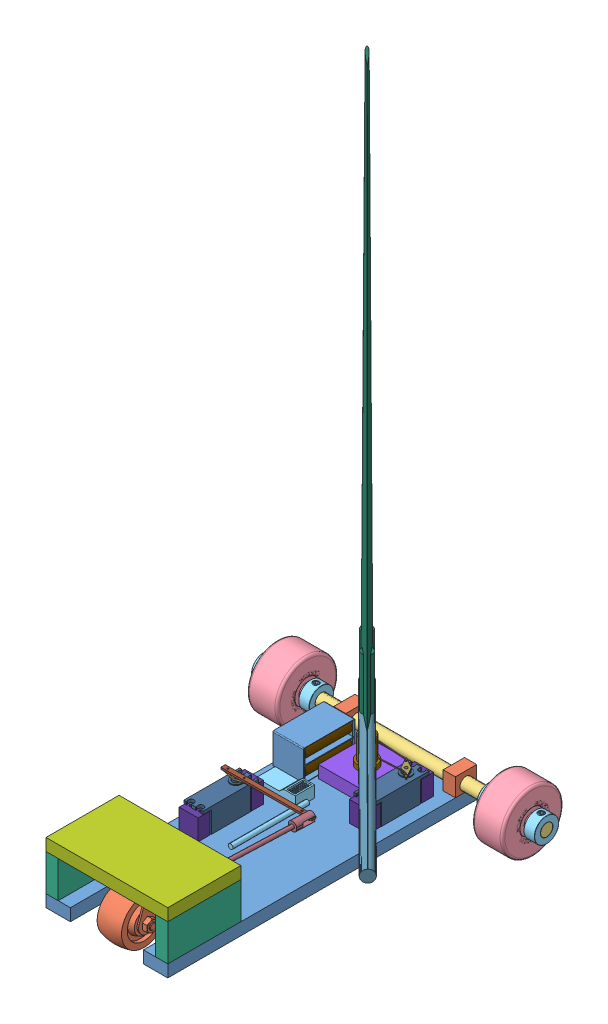
SolidWorks assembly SailCar, configuration Default. Lengths in mm.
Overall size (295.28 693.66 355.75).
43 component instances, 23 part files, 81 mates.
Components (placement in the parent):
- Base Board-1: Base Board [RW Steering] at (-13.5865 213.7638 364.5174) size (127 12.7 322.26)
- Rear Axel Mount-1: Rear Axel Mount [Default] at (100.7135 245.5138 145.4424) size (12.7 19.05 22.23)
- Rear Axel Mount-2: Rear Axel Mount [Default] at (-13.5865 245.5138 145.4424) size (12.7 19.05 22.23)
- Rear Axel-1: Rear Axel [Default] at (-97.724 234.0838 134.3299) x (1 0 0) z (0 -0.993806 0.111129) size (295.28 12.7 12.7)
- Colson Wheel-1: Colson Wheel [Default] at (-67.5615 234.0838 134.3299) x (1 0 0) z (0 -0.621172 0.783674) size (38.1 63.5 63.5)
- Colson Wheel-2: Colson Wheel [Default] at (167.3885 234.0838 134.3299) x (1 0 0) z (0 0.007106 0.999975) size (38.1 63.5 63.5)
- Collar-1: Collar [9414T11] at (-92.1678 234.0838 134.3299) x (0 0 1) z (-1 0 0) size (25.4 25.4 11.11)
- Collar-2: Collar [9414T11] at (191.9947 234.0838 134.3299) x (0 0 1) z (-1 0 0) size (25.4 25.4 11.11)
- Collar-3: Collar [9414T11] at (142.7822 234.0838 134.3299) x (0 0 1) z (-1 0 0) size (25.4 25.4 11.11)
- Collar-4: Collar [9414T11] at (-42.9553 234.0838 134.3299) x (0 0 1) z (-1 0 0) size (25.4 25.4 11.11)
- Riser-1: Riser [Default] at (100.7135 226.4638 445.4799) size (12.7 38.1 76.2)
- Riser-2: Riser [Default] at (-13.5865 226.4638 445.4799) size (12.7 38.1 76.2)
- Caster Mount-1: Caster Mount [Default] at (-13.5865 264.5638 445.4799) size (127 12.7 76.2)
- Mast Mount-1: Mast Mount [Default] at (24.5135 226.4638 199.4174) size (50.8 12.7 50.8)
- Bushing-1: Bushing [Default] at (49.9135 216.3038 174.0174) x (0.991208 0 -0.132316) z (0.132316 0 0.991208) size (20.32 25.4 20.32)
- Bushing-2: Bushing [Default] at (49.9135 267.1038 174.0174) x (-0.837169 0 -0.546944) z (-0.546944 0 0.837169) size (20.32 25.4 20.32)
- SteeringServo-1: SteeringServo [Default] at (45.4997 211.4215 255.6758) x (0 0 1) z (-1 0 0) size (145.66 47.29 94.14) (flexible)
  - Servo-1: Servo [Default] at (29.6042 21.3424 46.3862) size (58 43 20)
  - ServoArm-1: ServoArm [Default] at (14.3414 46.3165 49.8858) x (-0.999965 0 0.008374) z (-0.008374 0 -0.999965) size (4.6 1.95 94.1)
  - ServoHead-1: ServoHead [Default] at (14.2284 43.3424 36.3862) x (-0.999965 0 0.008374) z (-0.008374 0 -0.999965) size (7.62 2 25.64)
  - ServoRod-1: ServoRod [Default] at (78.5715 44.9395 -36.7193) x (-0.038321 0 0.999265) z (-0.999265 0 -0.038321) size (9.07 9.38 135.13)
- Sail Assembly-1: Sail Assembly [Default] at (-165.7996 107.2198 100.9953) x (0.705221 0 -0.708987) z (0.708987 0 0.705221) size (12.7 669.38 250.95) (flexible)
  - Sail Mast-1: Sail Mast [Default] at (100.3536 106.544 204.4346) size (12.7 114.3 250)
  - Sail Airfoil-1: Sail Airfoil [Default] at (100.3536 170.044 140.9846) x (0 0 1) z (-1 0 0) size (81.55 605.88 11)
  - Sail Sheet-1: Sail Sheet [Default] at (100.1872 170.044 390.9846) size (0.2 605.88 175)
- Servo-3: Servo [Default] at (80.7135 232.7638 189.4642) x (0 0 1) z (-1 0 0) size (58 43 20)
- ServoHead-1: ServoHead [Default] at (90.7135 254.7638 174.0884) x (0.705221 0 -0.708987) z (0.708987 0 0.705221) size (7.62 2 25.64)
- ServoMount-1: ServoMount [Default] at (9.1135 237.2588 251.1599) size (19.69 21.59 12.7)
- ServoMount-2: ServoMount [Default] at (9.1135 237.2588 319.3999) x (-1 0 0) z (0 0 -1) size (19.69 21.59 12.7)
- ServoMount-3: ServoMount [Default] at (90.7135 237.2588 223.5842) x (-1 0 0) z (0 0 -1) size (19.69 21.59 12.7)
- ServoMount-4: ServoMount [Default] at (90.7135 237.2588 155.3442) size (19.69 21.59 12.7)
- BatteryPack-1: BatteryPack [Default] at (-0.0437 191.6101 153.6458) x (-1 0 0) z (0 1 0) size (32 54 32)
  - Battery-1: Battery [Default] at (2.3118 6.4867 42.8537) size (14 49.5 14)
  - BatteryHolder-1: BatteryHolder [Default] at (-5.6882 31.4967 66.8537) x (0 -1 0) z (1 0 0) size (54 32 32)
  - Battery-2: Battery [Default] at (-13.6882 6.4867 58.8537) x (-1 0 0) z (0 0 -1) size (14 49.5 14)
  - Battery-3: Battery [Default] at (2.3118 6.4867 58.8537) size (14 49.5 14)
  - Battery-4: Battery [Default] at (-13.6882 6.4867 42.8537) x (0 0 1) z (-1 0 0) size (14 49.5 14)
- Steerable Caster-1: Steerable Caster [Default] at (22.217 195.6961 355.3362) size (57.95 63.5 75.41)
  - Caster-1: Caster [78155T41] at (27.6965 30.7677 63.95) size (47.62 63.5 75.41)
  - SteeringServoHead-1: SteeringServoHead [Default] at (49.0103 58.9487 43.8873) x (0 0 -1) z (1 0 0) size (7.62 2 14.89)
- string2-1: string2 [Default] at (84.6871 252.7638 168.0941) x (0.997451 0 0.071358) z (-0.071358 0 0.997451) size (47.9 6.04 1.03)
- string2-2: string2 [Default] at (96.7399 252.7638 180.0828) x (0.998759 0 -0.049796) z (0.049796 0 0.998759) size (47.9 6.04 1.03)
- Reciever-1: Reciever [Default] at (19.6896 226.6822 229.1129) x (-1 0 0) z (0 0 -1) size (46 12 90)
Mates (geometry in assembly coordinates):
- Coincident1: coincident anti-aligned: plane of Rear Axel Mount-1 through (113.4135 226.4638 145.4424) normal (0 -1 0); plane of Base Board-1 through (-13.5865 226.4638 364.5174) normal (0 1 0)
- Coincident2: coincident aligned: plane of Base Board-1 through (113.4135 226.4638 364.5174) normal (1 0 0); plane of Rear Axel Mount-1 through (113.4135 245.5138 145.4424) normal (1 0 0)
- Coincident3: coincident aligned: plane of Base Board-1 through (-13.5865 226.4638 123.2174) normal (0 0 -1); plane of Rear Axel Mount-1 through (113.4135 245.5138 123.2174) normal (0 0 -1)
- Coincident4: coincident aligned: plane of Base Board-1 through (-13.5865 226.4638 123.2174) normal (0 0 -1); plane of Rear Axel Mount-2 through (-0.8865 245.5138 123.2174) normal (0 0 -1)
- Coincident5: coincident anti-aligned: plane of Base Board-1 through (-13.5865 226.4638 364.5174) normal (0 1 0); plane of Rear Axel Mount-2 through (-0.8865 226.4638 145.4424) normal (0 -1 0)
- Coincident6: coincident aligned: plane of Base Board-1 through (-13.5865 226.4638 364.5174) normal (-1 0 0); plane of Rear Axel Mount-2 through (-13.5865 245.5138 145.4424) normal (-1 0 0)
- Concentric1: concentric aligned: cylinder of Rear Axel Mount-2 through (-0.8865 234.0838 134.3299) axis (-1 0 0) radius 6.35; cylinder of Rear Axel-1 through (197.551 234.0838 134.3299) axis (-1 0 0) radius 6.35
- Coincident7: coincident anti-aligned: plane of Base Board-1 through (49.9135 213.7638 364.5174) normal (-1 0 0); plane of Rear Axel-1
- Concentric2: concentric aligned: cylinder of Rear Axel-1 through (197.551 234.0838 134.3299) axis (-1 0 0) radius 6.35; cylinder of Colson Wheel-1 through (-48.5115 234.0838 134.3299) axis (-1 0 0) radius 6.35
- Concentric3: concentric aligned: cylinder of Rear Axel-1 through (197.551 234.0838 134.3299) axis (-1 0 0) radius 6.35; cylinder of Colson Wheel-2 through (186.4385 234.0838 134.3299) axis (-1 0 0) radius 6.35
- Concentric4: concentric anti-aligned: cylinder of Rear Axel-1 through (197.551 234.0838 134.3299) axis (-1 0 0) radius 6.35; cylinder of Collar-1 through (-97.724 234.0838 134.3299) axis (1 0 0) radius 6.35
- Coincident8: coincident aligned: plane of Rear Axel-1 through (-97.724 234.0838 134.3299) normal (-1 0 0); plane of Collar-1 through (-97.724 234.0838 134.3299) normal (-1 0 0)
- Coincident10: coincident anti-aligned: plane of Colson Wheel-1 through (-86.6115 234.0838 134.3299) normal (-1 0 0); plane of Collar-1 through (-86.6115 234.0838 134.3299) normal (1 0 0)
- Concentric5: concentric anti-aligned: cylinder of Rear Axel-1 through (197.551 234.0838 134.3299) axis (-1 0 0) radius 6.35; cylinder of Collar-4 through (-48.5115 234.0838 134.3299) axis (1 0 0) radius 6.35
- Coincident11: coincident anti-aligned: plane of Colson Wheel-1 through (-48.5115 234.0838 134.3299) normal (1 0 0); plane of Collar-4 through (-48.5115 234.0838 134.3299) normal (-1 0 0)
- Concentric6: concentric anti-aligned: cylinder of Rear Axel-1 through (197.551 234.0838 134.3299) axis (-1 0 0) radius 6.35; cylinder of Collar-2 through (186.4385 234.0838 134.3299) axis (1 0 0) radius 6.35
- Coincident12: coincident aligned: plane of Rear Axel-1 through (197.551 234.0838 134.3299) normal (1 0 0); plane of Collar-2 through (197.551 234.0838 134.3299) normal (1 0 0)
- Coincident13: coincident anti-aligned: plane of Colson Wheel-2 through (186.4385 234.0838 134.3299) normal (1 0 0); plane of Collar-2 through (186.4385 234.0838 134.3299) normal (-1 0 0)
- Concentric7: concentric anti-aligned: cylinder of Rear Axel-1 through (197.551 234.0838 134.3299) axis (-1 0 0) radius 6.35; cylinder of Collar-3 through (137.226 234.0838 134.3299) axis (1 0 0) radius 6.35
- Coincident14: coincident anti-aligned: plane of Colson Wheel-2 through (148.3385 234.0838 134.3299) normal (-1 0 0); plane of Collar-3 through (148.3385 234.0838 134.3299) normal (1 0 0)
- Coincident15: coincident anti-aligned: plane of Base Board-1 through (-13.5865 226.4638 364.5174) normal (0 1 0); plane of Riser-1 through (113.4135 226.4638 445.4799) normal (0 -1 0)
- Coincident16: coincident aligned: plane of Base Board-1 through (113.4135 226.4638 364.5174) normal (1 0 0); plane of Riser-1 through (113.4135 226.4638 445.4799) normal (1 0 0)
- Coincident17: coincident aligned: plane of Base Board-1 through (-13.5865 226.4638 445.4799) normal (0 0 1); plane of Riser-1 through (113.4135 226.4638 445.4799) normal (0 0 1)
- Coincident18: coincident aligned: plane of Base Board-1 through (-13.5865 226.4638 445.4799) normal (0 0 1); plane of Riser-2 through (-0.8865 226.4638 445.4799) normal (0 0 1)
- Coincident19: coincident aligned: plane of Base Board-1 through (-13.5865 226.4638 364.5174) normal (-1 0 0); plane of Riser-2 through (-13.5865 226.4638 445.4799) normal (-1 0 0)
- Coincident20: coincident anti-aligned: plane of Base Board-1 through (-13.5865 226.4638 364.5174) normal (0 1 0); plane of Riser-2 through (-0.8865 226.4638 445.4799) normal (0 -1 0)
- Coincident21: coincident anti-aligned: plane of Riser-1 through (113.4135 264.5638 445.4799) normal (0 1 0); plane of Caster Mount-1 through (-13.5865 264.5638 445.4799) normal (0 -1 0)
- Coincident22: coincident aligned: plane of Riser-1 through (113.4135 226.4638 445.4799) normal (1 0 0); plane of Caster Mount-1 through (113.4135 277.2638 445.4799) normal (1 0 0)
- Coincident23: coincident aligned: plane of Caster Mount-1 through (-13.5865 277.2638 445.4799) normal (0 0 1); plane of Riser-1 through (113.4135 226.4638 445.4799) normal (0 0 1)
- Concentric8: concentric aligned: cylinder of Base Board-1 through (49.9135 226.4638 174.0174) axis (0 -1 0) radius 7.874; cylinder of Mast Mount-1 through (49.9135 239.1638 174.0174) axis (0 -1 0) radius 7.874
- Coincident28: coincident anti-aligned: plane of Base Board-1 through (-13.5865 226.4638 364.5174) normal (0 1 0); plane of Mast Mount-1 through (24.5135 226.4638 199.4174) normal (0 -1 0)
- Concentric9: concentric aligned: cylinder of Mast Mount-1 through (49.9135 239.1638 174.0174) axis (0 -1 0) radius 7.874; cylinder of Bushing-1 through (49.9135 241.7038 174.0174) axis (0 -1 0) radius 7.874
- Concentric10: concentric aligned: cylinder of Mast Mount-1 through (49.9135 239.1638 174.0174) axis (0 -1 0) radius 7.874; cylinder of Bushing-1 through (49.9135 241.7038 174.0174) axis (0 -1 0) radius 7.874
- Coincident29: coincident anti-aligned: plane of Mast Mount-1 through (24.5135 239.1638 199.4174) normal (0 1 0); plane of Bushing-1 through (49.9135 239.1638 174.0174) normal (0 -1 0)
- Coincident32: coincident anti-aligned: plane of Bushing-1 through (49.9135 241.7038 174.0174) normal (0 1 0); plane of Bushing-2 through (49.9135 241.7038 174.0174) normal (0 -1 0)
- Coincident45: coincident aligned: plane of Base Board-1 through (-13.5865 213.7638 364.5174) normal (0 -1 0); plane of SteeringServo-1/Servo-1 through (19.1135 213.7638 305.7799) normal (0 -1 0)
- Parallel2: parallel anti-aligned: plane of SteeringServo-1/Servo-1 through (19.1135 213.7638 264.7799) normal (0 0 -1); plane of assembly through (0 0 0) normal (0 0 1)
- Concentric11: concentric anti-aligned: cylinder of Bushing-2 through (49.9135 241.7038 174.0174) axis (0 1 0) radius 6.604; cylinder of Sail Assembly-1/Sail Mast-1 through (49.9135 270.9138 174.0174) axis (0 -1 0) radius 6.35
- Distance9: distance = 27.94 mm aligned: plane of Bushing-2 through (49.9135 241.7038 174.0174) normal (0 -1 0); plane of Sail Assembly-1/Sail Mast-1 through (49.9135 213.7638 174.0174) normal (0 -1 0)
- Coincident48: coincident anti-aligned: plane of Bushing-1 through (49.9135 241.7038 174.0174) normal (0 1 0); plane of Bushing-2 through (49.9135 241.7038 174.0174) normal (0 -1 0)
- Concentric12: concentric aligned: cylinder of Bushing-1 through (49.9135 241.7038 174.0174) axis (0 -1 0) radius 6.604; cylinder of Sail Assembly-1/Sail Mast-1 through (49.9135 270.9138 174.0174) axis (0 -1 0) radius 6.35
- Parallel3: parallel aligned: plane of Base Board-1 through (113.4135 226.4638 364.5174) normal (1 0 0); plane of Mast Mount-1 through (75.3135 239.1638 199.4174) normal (1 0 0)
- Distance10: distance = 63.5 mm anti-aligned: plane of SteeringServo-1/Servo-1 through (19.1135 213.7638 305.7799) normal (0 0 1); plane of Riser-1 through (113.4135 226.4638 369.2799) normal (0 0 -1)
- Parallel4: parallel anti-aligned: plane of Mast Mount-1 through (75.3135 239.1638 199.4174) normal (1 0 0); plane of Servo-3 through (80.7135 232.7638 189.4642) normal (-1 0 0)
- Distance11: distance = 12.7 mm aligned: plane of Base Board-1 through (113.4135 226.4638 364.5174) normal (1 0 0); plane of Servo-3 through (100.7135 232.7638 189.4642) normal (1 0 0)
- Distance12: distance = 45.7468 mm aligned: plane of Servo-3 through (100.7135 213.7638 168.9642) normal (0 0 -1); plane of Base Board-1 through (-13.5865 226.4638 123.2174) normal (0 0 -1)
- Coincident58: coincident aligned: plane of Base Board-1 through (-13.5865 213.7638 364.5174) normal (0 -1 0); plane of Servo-3 through (100.7135 213.7638 209.9642) normal (0 -1 0)
- Parallel6: parallel aligned: plane of ServoHead-1 through (90.7135 254.7638 174.0884) normal (0.705221 0 -0.708987); plane of Sail Assembly-1 through (-165.7996 107.2198 100.9953) normal (0.705221 0 -0.708987)
- Coincident60: coincident anti-aligned: plane of Servo-3 through (90.7135 254.7638 174.0884) normal (0 1 0); plane of ServoHead-1 through (90.7135 254.7638 174.0884) normal (0 -1 0)
- Concentric16: concentric aligned: cylinder of Servo-3 through (90.7135 256.7638 174.0884) axis (0 -1 0) radius 1.5; cylinder of ServoHead-1 through (90.7135 256.7638 174.0884) axis (0 -1 0) radius 1.5
- Coincident61: coincident anti-aligned: plane of Base Board-1 through (-13.5865 226.4638 364.5174) normal (0 1 0); plane of ServoMount-1 through (18.956 226.4638 263.8599) normal (0 -1 0)
- Concentric17: concentric aligned: cylinder of SteeringServo-1/Servo-1 through (4.1135 213.7638 258.7799) axis (0 1 0) radius 3; cylinder of ServoMount-1 through (4.1135 241.7038 258.7799) axis (0 1 0) radius 1.5875
- Concentric18: concentric aligned: cylinder of SteeringServo-1/Servo-1 through (14.1135 213.7638 258.7799) axis (0 1 0) radius 3; cylinder of ServoMount-1 through (14.1135 241.7038 258.7799) axis (0 1 0) radius 1.5875
- Coincident62: coincident anti-aligned: plane of Base Board-1 through (-13.5865 226.4638 364.5174) normal (0 1 0); plane of ServoMount-2 through (-0.729 226.4638 306.6999) normal (0 -1 0)
- Coincident63: coincident anti-aligned: plane of Base Board-1 through (-13.5865 226.4638 364.5174) normal (0 1 0); plane of ServoMount-3 through (80.871 226.4638 210.8842) normal (0 -1 0)
- Coincident64: coincident anti-aligned: plane of Base Board-1 through (-13.5865 226.4638 364.5174) normal (0 1 0); plane of ServoMount-4 through (100.556 226.4638 168.0442) normal (0 -1 0)
- Concentric29: concentric aligned: cylinder of Servo-3 through (95.7135 213.7638 162.9642) axis (0 1 0) radius 3; cylinder of ServoMount-4 through (95.7135 241.7038 162.9642) axis (0 1 0) radius 1.5875
- Concentric30: concentric aligned: cylinder of Servo-3 through (85.7135 213.7638 162.9642) axis (0 1 0) radius 3; cylinder of ServoMount-4 through (85.7135 241.7038 162.9642) axis (0 1 0) radius 1.5875
- Concentric31: concentric aligned: cylinder of SteeringServo-1/Servo-1 through (4.1135 213.7638 311.7799) axis (0 1 0) radius 3; cylinder of ServoMount-2 through (4.1135 241.7038 311.7799) axis (0 1 0) radius 1.5875
- Concentric32: concentric aligned: cylinder of SteeringServo-1/Servo-1 through (14.1135 213.7638 311.7799) axis (0 1 0) radius 3; cylinder of ServoMount-2 through (14.1135 241.7038 311.7799) axis (0 1 0) radius 1.5875
- Concentric34: concentric aligned: cylinder of Servo-3 through (85.7135 213.7638 215.9642) axis (0 1 0) radius 3; cylinder of ServoMount-3 through (85.7135 241.7038 215.9642) axis (0 1 0) radius 1.5875
- Concentric35: concentric aligned: cylinder of Servo-3 through (95.7135 213.7638 215.9642) axis (0 1 0) radius 3; cylinder of ServoMount-3 through (95.7135 241.7038 215.9642) axis (0 1 0) radius 1.5875
- Distance13: distance = 12.7 mm aligned: plane of SteeringServo-1/Servo-1 through (-0.8865 232.7638 285.2799) normal (-1 0 0); plane of Base Board-1 through (-13.5865 226.4638 364.5174) normal (-1 0 0)
- Coincident65: coincident anti-aligned: plane of Base Board-1 through (-13.5865 226.4638 364.5174) normal (0 1 0); plane of BatteryPack-1/BatteryHolder-1 through (5.6445 226.4638 185.1424) normal (0 -1 0)
- Parallel7: parallel anti-aligned: plane of ServoMount-3 through (90.7135 237.2588 223.5842) normal (0 0 1); plane of BatteryPack-1/BatteryHolder-1 through (-10.3555 226.4638 158.1424) normal (0 0 -1)
- Parallel8: parallel anti-aligned: plane of Rear Axel Mount-2 through (-0.8865 245.5138 145.4424) normal (0 0 1); plane of BatteryPack-1/BatteryHolder-1 through (-10.3555 226.4638 158.1424) normal (0 0 -1)
- Distance14: distance = 12.7 mm anti-aligned: plane of Rear Axel Mount-2 through (-0.8865 245.5138 145.4424) normal (0 0 1); plane of BatteryPack-1/BatteryHolder-1 through (-10.3555 226.4638 158.1424) normal (0 0 -1)
- Coincident70: coincident anti-aligned: plane of Caster Mount-1 through (-13.5865 264.5638 445.4799) normal (0 -1 0); plane of Steerable Caster-1/Caster-1 through (26.101 264.5638 369.2799) normal (0 1 0)
- Coincident72: coincident aligned: line of Steerable Caster-1/Caster-1 through (73.726 264.5638 369.2799) axis (-1 0 0); line of Caster Mount-1 through (113.4135 264.5638 369.2799) axis (-1 0 0)
- Coincident76: coincident: moEndPointRef_w of Steerable Caster-1/Caster-1; line of assembly
- Concentric37: concentric anti-aligned: cylinder of ServoHead-1 through (84.6871 252.6425 168.0941) axis (0 1 0) radius 0.75; cylinder of string2-1 through (84.6871 255.7638 168.0941) axis (0 -1 0) radius 0.4445
- Concentric38: concentric anti-aligned: cylinder of ServoHead-1 through (96.7399 252.6425 180.0828) axis (0 1 0) radius 0.75; cylinder of string2-2 through (96.7399 255.7638 180.0828) axis (0 -1 0) radius 0.4445
- Coincident77: coincident anti-aligned: plane of Servo-3 through (90.7135 252.7638 174.0884) normal (0 1 0); plane of string2-2 through (96.7399 252.7638 180.0828) normal (0 -1 0)
- Coincident78: coincident anti-aligned: plane of Servo-3 through (90.7135 252.7638 174.0884) normal (0 1 0); plane of string2-1 through (84.6871 252.7638 168.0941) normal (0 -1 0)
- TEMP: parallel aligned: plane of assembly through (0 0 0) normal (1 0 0); plane of Sail Assembly-1
- Tangent1: tangent: cylinder of Bushing-2 through (49.9135 241.7038 174.0174) axis (0 1 0) radius 7.874; face of string2-1
- Tangent6: tangent: cylinder of Bushing-2 through (49.9135 241.7038 174.0174) axis (0 1 0) radius 7.874; face of string2-2
- Concentric40: concentric anti-aligned: cylinder of SteeringServo-1/ServoRod-1 through (79.7272 260.5081 399.2235) axis (0 -1 0) radius 0.635; cylinder of Steerable Caster-1/SteeringServoHead-1 through (79.7272 252.5235 399.2235) axis (0 1 0) radius 0.75
- Coincident79: coincident anti-aligned: plane of Base Board-1 through (-13.5865 226.4638 364.5174) normal (0 1 0); plane of Reciever-1 through (-0.8865 226.4638 239.1129) normal (0 -1 0)
- Parallel9: parallel aligned: plane of Reciever-1 through (40.1135 238.4638 239.1129) normal (1 0 0); plane of assembly through (0 0 0) normal (1 0 0)
- Distance15: distance = 12.7 mm: plane of Reciever-1 through (-0.8865 226.4638 239.1129) normal (-1 0 0); line of Base Board-1 through (-13.5865 226.4638 445.4799) axis (0 0 -1)
